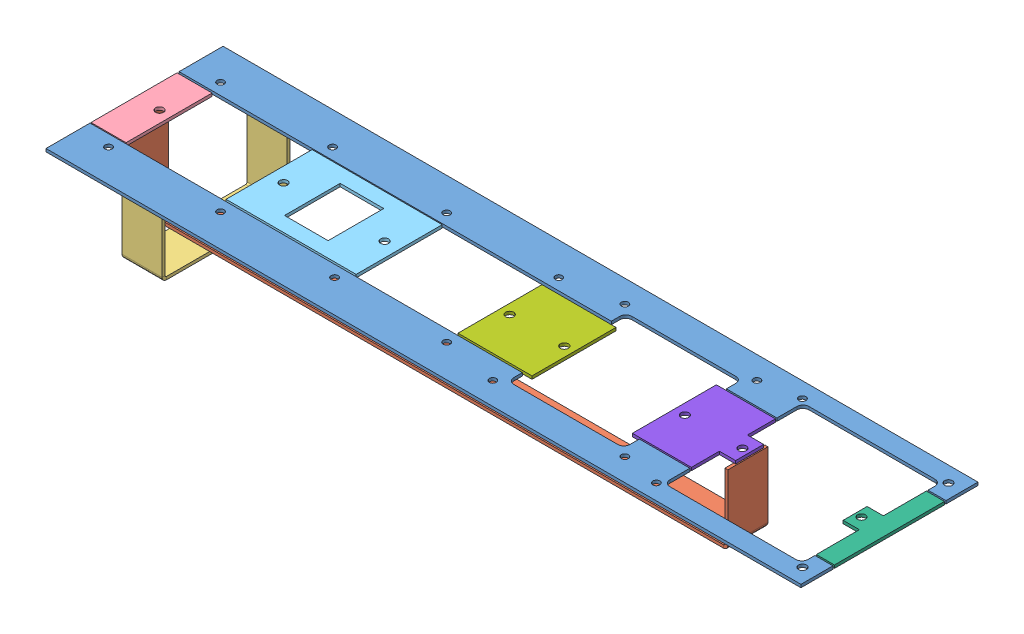
SolidWorks assembly КаркасРозетокH_ВК, configuration По умолчанию. Lengths in mm.
Overall size (377.3 39 88.5).
9 component instances, 8 part files, 21 mates.
Components (placement in the parent):
- ПластинаДH_ВК-1: ПластинаДH_ВК [По умолчанию] at (0 1.5 0) x (1 0 0) z (0 0 -1) size (377.3 1.5 22.5)
- ПластинаДH_ВК-2: ПластинаДH_ВК [По умолчанию] at (0 0 88.5) size (377.3 1.5 22.5)
- СкобаД3_ВК-1: СкобаД3_ВК [По умолчанию] at (6 -34.5 54.714) size (301 35 20)
- СкобаES-1: СкобаES [По умолчанию] at (47.9944 -36 78.5) x (0 0 -1) z (1 0 0) size (64 36.5 20)
- ПеремычкаES1-1: ПеремычкаES1 [По умолчанию] at (17.5 0 66) x (0 0 -1) z (1 0 0) size (43 1.5 17.5)
- ПеремычкаES2SW-1: ПеремычкаES2SW [По умолчанию] at (132 0 65.5) x (0 0 -1) z (1 0 0) size (43 1.5 65)
- ПеремычкаUS-1: ПеремычкаUS [По умолчанию] at (377.3 0 71.75) x (0 0 -1) z (1 0 0) size (55 1.5 17.16)
- ПеремычкаES2H-1: ПеремычкаES2H [По умолчанию] at (219.8898 0 65.5) x (0 0 -1) z (1 0 0) size (42 1.5 37)
- ПеремычкаESUSH-1: ПеремычкаESUSH [По умолчанию] at (269.8035 0 23.25) x (0 0 1) z (-1 0 0) size (42 1.5 37.61)
Mates (geometry in assembly coordinates):
- Совпадение4: coincident aligned: plane of ПластинаДH_ВК-1 through (0 0 0) normal (-1 0 0); plane of ПластинаДH_ВК-2 through (0 1.5 88.5) normal (-1 0 0)
- Совпадение5: coincident aligned: plane of ПластинаДH_ВК-1 through (219.05 1.5 17.75) normal (0 1 0); plane of ПластинаДH_ВК-2 through (219.05 1.5 70.75) normal (0 1 0)
- Совпадение7: coincident aligned: plane of ПластинаДH_ВК-1 through (219.05 1.5 17.75) normal (0 1 0); plane of ПеремычкаUS-1 through (377.3 1.5 71.75) normal (0 1 0)
- Совпадение8: coincident aligned: plane of ПластинаДH_ВК-1 through (377.3 0 16) normal (1 0 0); plane of ПеремычкаUS-1 through (377.3 1.5 71.75) normal (1 0 0)
- Расстояние3: distance = 0.75 mm anti-aligned: plane of ПеремычкаUS-1 through (377.3 1.5 16.75) normal (0 0 -1); plane of ПластинаДH_ВК-1 through (368.3 0 16) normal (0 0 1)
- Расстояние4: distance = 0.75 mm anti-aligned: plane of ПеремычкаUS-1 through (377.3 1.5 71.75) normal (0 0 1); plane of ПластинаДH_ВК-2 through (368.3 1.5 72.5) normal (0 0 -1)
- Расстояние6: distance = 0 mm anti-aligned: plane of ПеремычкаES2SW-1 through (132 1.5 22.5) normal (0 0 -1); plane of ПластинаДH_ВК-1 through (299.3 0 22.5) normal (0 0 1)
- Совпадение15: coincident aligned: plane of ПластинаДH_ВК-1 through (219.05 1.5 17.75) normal (0 1 0); plane of ПеремычкаES2SW-1 through (132 1.5 65.5) normal (0 1 0)
- Совпадение16: coincident aligned: plane of ПластинаДH_ВК-1 through (219.05 1.5 17.75) normal (0 1 0); plane of ПеремычкаES2H-1 through (219.8898 1.5 65.5) normal (0 1 0)
- Расстояние7: distance = 1 mm anti-aligned: plane of ПеремычкаES2H-1 through (219.8898 1.5 23.5) normal (0 0 -1); plane of ПластинаДH_ВК-1 through (299.3 0 22.5) normal (0 0 1)
- Совпадение18: coincident aligned: plane of ПластинаДH_ВК-1 through (219.05 1.5 17.75) normal (0 1 0); plane of ПеремычкаES1-1 through (17.5 1.5 66) normal (0 1 0)
- Расстояние8: distance = 0.5 mm anti-aligned: plane of ПластинаДH_ВК-1 through (299.3 0 22.5) normal (0 0 1); plane of ПеремычкаES1-1 through (17.5 1.5 23) normal (0 0 -1)
- Совпадение20: coincident aligned: plane of ПластинаДH_ВК-2 through (0 1.5 88.5) normal (-1 0 0); plane of ПеремычкаES1-1 through (0 1.5 66) normal (-1 0 0)
- Расстояние9: distance = 1 mm anti-aligned: plane of СкобаД3_ВК-1 through (6 -1 34.714) normal (0 1 0); plane of ПеремычкаES1-1 through (17.5 0 66) normal (0 -1 0)
- Расстояние10: distance = 6 mm aligned: plane of СкобаД3_ВК-1 through (6 -34.5 54.714) normal (-1 0 0); plane of ПеремычкаES1-1 through (0 1.5 66) normal (-1 0 0)
- Расстояние11: distance = 1 mm anti-aligned: plane of СкобаES-1 through (27.9944 -1 78.5) normal (0 1 0); plane of ПластинаДH_ВК-2 through (219.05 0 70.75) normal (0 -1 0)
- Расстояние12: distance = 10 mm aligned: plane of СкобаES-1 through (47.9944 -36 78.5) normal (0 0 1); plane of ПластинаДH_ВК-2 through (0 1.5 88.5) normal (0 0 1)
- Совпадение21: coincident aligned: plane of ПластинаДH_ВК-1 through (219.05 1.5 17.75) normal (0 1 0); plane of ПеремычкаESUSH-1 through (269.8035 1.5 23.25) normal (0 1 0)
- Расстояние13: distance = 0.75 mm anti-aligned: plane of ПеремычкаESUSH-1 through (269.8035 1.5 23.25) normal (0 0 -1); plane of ПластинаДH_ВК-1 through (299.3 0 22.5) normal (0 0 1)
- Совпадение22: coincident aligned: plane of ПластинаДH_ВК-2 through (299.3 1.5 66) normal (1 0 0); plane of ПеремычкаESUSH-1 through (299.3 1.5 51.25) normal (1 0 0)
- Расстояние14: distance = 67 mm aligned: plane of ПластинаДH_ВК-2 through (0 1.5 88.5) normal (-1 0 0); plane of ПеремычкаES2SW-1 through (67 1.5 65.5) normal (-1 0 0)
